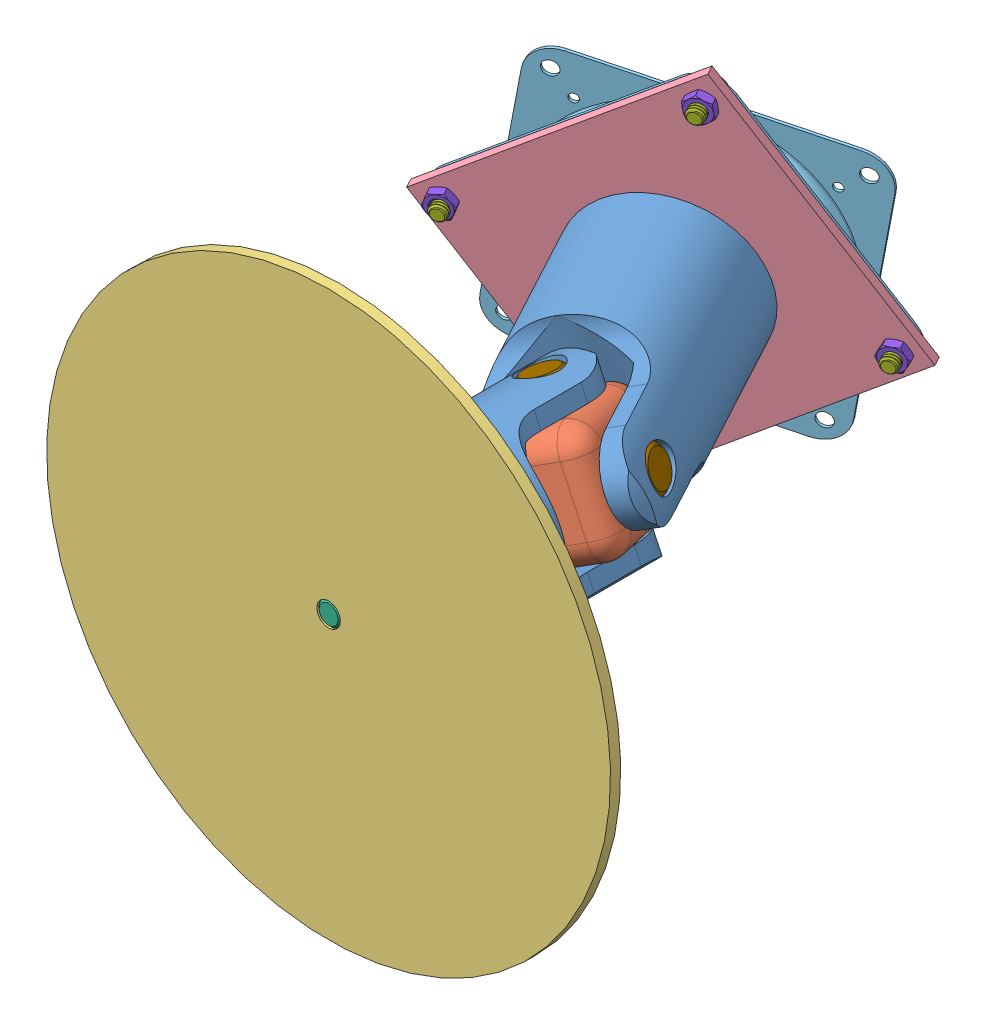
SolidWorks assembly THE_DESIGN, configuration Default. Lengths in mm.
Overall size (177.34 177.34 151.11).
20 component instances, 9 part files, 37 mates.
Components (placement in the parent):
- BandS-4: BandS [2456K19] at (14.9451 4.1501 -66.2661) x (0 0 -1) z (-0.90616 -0.422935 0) size (74.61 44.45 48.36)
- Block-2: Block [Default] at (15.7688 4.5345 -63.9692) x (-0.422935 0.90616 0) z (0.842579 0.39326 -0.367977) size (29.6 29.6 29.6)
- BandS-5: BandS [2456K19] at (16.5925 4.9189 -61.6724) x (0.435787 -0.09635 0.894878) z (-0.316465 0.914365 0.25256) size (74.61 44.45 48.36)
- Base-2: Base [Default] at (14.9451 4.1501 -2.7661) x (-0.983677 0.179942 0) z (0.179942 0.983677 0) size (152.4 38.33 152.4)
- Plate for Turntable-2: Plate for Turntable [Default] at (-12.1869 11.2819 -120.7701) x (-0.482689 0.814165 0.322719) z (0.759672 0.572584 -0.308295) size (76.2 2.54 76.2)
- Square Turntable-1: Square Turntable [6031K16] at (-14.3373 11.7561 -125.0648) x (0.195857 0.980579 0.010199) z (-0.878482 0.170823 0.446194) size (101.18 8.13 101.18)
- Dowel Pin for Top Plate-1: Dowel Pin for Top Plate [90145A815] at (-10.7341 10.9607 -117.7868) x (-0.435787 0.09635 -0.894878) z (-0.298955 -0.9533 0.042945) size (7.94 6.35 6.35)
- Screw for Top Plate-1: Screw for Top Plate [91735A191] at (31.3428 2.7338 -134.8417) x (-0.776957 0.461627 0.428064) z (-0.435787 0.09635 -0.894878) size (8.18 8.18 10.92)
- Screw for Top Plate-2: Screw for Top Plate [91735A191] at (-0.0803 55.7361 -113.8327) x (-0.776957 0.461627 0.428064) z (-0.435787 0.09635 -0.894878) size (8.18 8.18 10.92)
- Screw for Top Plate-3: Screw for Top Plate [91735A191] at (-49.5351 18.4607 -93.7626) x (-0.824863 0.355066 0.43992) z (-0.435787 0.09635 -0.894878) size (8.18 8.18 10.92)
- Screw for Top Plate-4: Screw for Top Plate [91735A191] at (-18.112 -34.5415 -114.7717) x (-0.776957 0.461627 0.428064) z (-0.435787 0.09635 -0.894878) size (8.18 8.18 10.92)
- Hex Nut-1: Hex Nut [90760A009] at (29.8305 3.0681 -137.9472) x (0.776957 -0.461627 -0.428064) z (0.454344 0.881826 -0.126311) size (6.35 2.99 7.33)
- Hex Nut-2: Hex Nut [90760A009] at (-1.5926 56.0704 -116.9381) x (0.377161 0.922297 -0.084367) z (-0.817215 0.374279 0.438264) size (6.35 2.99 7.33)
- Hex Nut-3: Hex Nut [90760A009] at (-19.1857 -34.017 -118.0702) x (0.293981 -0.924484 -0.2427) z (-0.850685 -0.368843 0.374553) size (6.35 2.99 7.33)
- Hex Nut-4: Hex Nut [90760A009] at (-51.5064 18.6956 -96.6553) x (-0.13288 0.976471 0.169845) z (0.890187 0.192928 -0.41273) size (6.35 2.99 7.33)
- Dowel Pin for Top Plate-2: Dowel Pin for Top Plate [90145A815] at (14.9451 4.1501 -3.9688) x (0 0 -1) z (0.392839 -0.919607 0) size (7.94 6.35 6.35)
- Dowel Pin for U-Joint-8: Dowel Pin for U-Joint [98381A665] at (29.4922 10.9397 -67.3061) x (0.842579 0.39326 -0.367977) z (-0.421823 0.906673 0.003094) size (12.7 11.11 11.11)
- Dowel Pin for U-Joint-9: Dowel Pin for U-Joint [98381A665] at (8.4701 18.0232 -66.2661) x (0.422935 -0.90616 0) z (0 0 1) size (12.7 11.11 11.11)
- Dowel Pin for U-Joint-10: Dowel Pin for U-Joint [98381A665] at (21.4202 -9.7231 -66.2661) x (0.422935 -0.90616 0) z (0 0 -1) size (12.7 11.11 11.11)
- Dowel Pin for U-Joint-11: Dowel Pin for U-Joint [98381A665] at (3.6927 -1.1018 -56.0387) x (0.842579 0.39326 -0.367977) z (-0.504894 0.814588 -0.28553) size (12.7 11.11 11.11)
Mates (geometry in assembly coordinates):
- Concentric4: concentric: cylinder of BandS-4 through (5.5454 24.2895 -66.2661) axis (0.422935 -0.90616 0) radius 5.5563; cylinder of Block-2 through (18.7346 -3.969 -66.2661) axis (0.422935 -0.90616 0) radius 5.588
- Coincident23: coincident: plane of BandS-4 through (28.8243 26.9626 -48.0225) normal (0.422935 -0.90616 0); plane of Block-2 through (1.9725 14.43 -44.7592) normal (-0.422935 0.90616 0)
- Concentric7: concentric: cylinder of BandS-5 through (-8.3127 10.4253 -112.8147) axis (-0.435787 0.09635 -0.894878) radius 3.175; cylinder of Plate for Turntable-2 through (-12.1869 11.2819 -120.7701) axis (0.435787 -0.09635 0.894878) radius 3.175
- Concentric8: concentric: cylinder of Plate for Turntable-2 through (28.2047 3.4276 -141.2857) axis (0.435787 -0.09635 0.894878) radius 2.032; cylinder of Square Turntable-1 through (27.8837 3.4986 -141.9448) axis (-0.435787 0.09635 -0.894878) radius 1.9844
- Coincident27: coincident: plane of Plate for Turntable-2 through (-12.1869 11.2819 -120.7701) normal (-0.435787 0.09635 -0.894878); plane of Square Turntable-1 through (-5.4658 45.1777 -120.3936) normal (0.435787 -0.09635 0.894878)
- Parallel15: parallel: plane of Plate for Turntable-2 through (-21.6331 -41.798 -119.0467) normal (-0.759672 -0.572584 0.308295); plane of Square Turntable-1 through (-126.3031 35.25 -233.743) normal (-0.759672 -0.572584 0.308295)
- Concentric14: concentric: cylinder of BandS-5 through (-8.3127 10.4253 -112.8147) axis (-0.435787 0.09635 -0.894878) radius 3.175; cylinder of Dowel Pin for Top Plate-1 through (-9.0046 10.5783 -114.2353) axis (-0.435787 0.09635 -0.894878) radius 3.175
- Coincident34: coincident: circle of Plate for Turntable-2; circle of Dowel Pin for Top Plate-1
- Coincident36: coincident: plane of Square Turntable-1 through (-5.7868 45.2487 -121.0528) normal (-0.435787 0.09635 -0.894878); plane of Screw for Top Plate-1 through (27.8837 3.4986 -141.9448) normal (0.435787 -0.09635 0.894878)
- Concentric16: concentric: cylinder of Square Turntable-1 through (27.8837 3.4986 -141.9448) axis (-0.435787 0.09635 -0.894878) radius 1.9844; cylinder of Screw for Top Plate-1 through (31.3428 2.7338 -134.8417) axis (-0.435787 0.09635 -0.894878) radius 2.0828
- Coincident37: coincident: plane of Square Turntable-1 through (-5.7868 45.2487 -121.0528) normal (-0.435787 0.09635 -0.894878); plane of Screw for Top Plate-2 through (-3.5394 56.5009 -120.9358) normal (0.435787 -0.09635 0.894878)
- Concentric17: concentric: cylinder of Square Turntable-1 through (-3.5394 56.5009 -120.9358) axis (-0.435787 0.09635 -0.894878) radius 1.9844; cylinder of Screw for Top Plate-2 through (-0.0803 55.7361 -113.8327) axis (-0.435787 0.09635 -0.894878) radius 2.0828
- Coincident38: coincident: plane of Square Turntable-1 through (-5.7868 45.2487 -121.0528) normal (-0.435787 0.09635 -0.894878); plane of Screw for Top Plate-3 through (-52.9942 19.2255 -100.8657) normal (0.435787 -0.09635 0.894878)
- Concentric18: concentric: cylinder of Square Turntable-1 through (-52.9942 19.2255 -100.8657) axis (-0.435787 0.09635 -0.894878) radius 1.9844; cylinder of Screw for Top Plate-3 through (-49.5351 18.4607 -93.7626) axis (-0.435787 0.09635 -0.894878) radius 2.0828
- Coincident39: coincident: plane of Square Turntable-1 through (-5.7868 45.2487 -121.0528) normal (-0.435787 0.09635 -0.894878); plane of Screw for Top Plate-4 through (-21.5711 -33.7768 -121.8748) normal (0.435787 -0.09635 0.894878)
- Concentric19: concentric: cylinder of Square Turntable-1 through (-21.5711 -33.7768 -121.8748) axis (-0.435787 0.09635 -0.894878) radius 1.9844; cylinder of Screw for Top Plate-4 through (-18.112 -34.5415 -114.7717) axis (-0.435787 0.09635 -0.894878) radius 2.0828
- Concentric21: concentric: cylinder of Screw for Top Plate-1 through (31.3428 2.7338 -134.8417) axis (-0.435787 0.09635 -0.894878) radius 2.0828; cylinder of Hex Nut-1 through (29.3116 3.1829 -139.0127) axis (0.435787 -0.09635 0.894878) radius 2.0828
- Coincident42: coincident: plane of Plate for Turntable-2 through (-11.08 11.0371 -118.4971) normal (0.435787 -0.09635 0.894878); plane of Hex Nut-2 through (-1.8109 52.5708 -118.5391) normal (-0.435787 0.09635 -0.894878)
- Concentric22: concentric: cylinder of Screw for Top Plate-2 through (-0.0803 55.7361 -113.8327) axis (-0.435787 0.09635 -0.894878) radius 2.0828; cylinder of Hex Nut-2 through (-2.1115 56.1852 -118.0036) axis (0.435787 -0.09635 0.894878) radius 2.0828
- Coincident43: coincident: plane of Plate for Turntable-2 through (-11.08 11.0371 -118.4971) normal (0.435787 -0.09635 0.894878); plane of Hex Nut-3 through (-19.0786 -30.2909 -119.0517) normal (-0.435787 0.09635 -0.894878)
- Tangent13: tangent: cylinder of Screw for Top Plate-4 through (-18.112 -34.5415 -114.7717) axis (-0.435787 0.09635 -0.894878) radius 2.0828; face of Hex Nut-3
- Coincident44: coincident: plane of Plate for Turntable-2 through (-11.08 11.0371 -118.4971) normal (0.435787 -0.09635 0.894878); plane of Hex Nut-4 through (-53.2351 15.3564 -97.5034) normal (-0.435787 0.09635 -0.894878)
- Tangent16: tangent: cylinder of Screw for Top Plate-3 through (-49.5351 18.4607 -93.7626) axis (-0.435787 0.09635 -0.894878) radius 2.0828; face of Hex Nut-4
- Coincident45: coincident: plane of Base-2 through (14.9451 4.1501 0) normal (0 0 1); plane of Dowel Pin for Top Plate-2 through (14.9451 4.1501 0) normal (0 0 1)
- Concentric24: concentric: cylinder of Base-2 through (14.9451 4.1501 0) axis (0 0 -1) radius 3.175; cylinder of Dowel Pin for Top Plate-2 through (14.9451 4.1501 0) axis (0 0 -1) radius 3.175
- Coincident59: coincident: plane of Plate for Turntable-2 through (-11.08 11.0371 -118.4971) normal (0.435787 -0.09635 0.894878); plane of Hex Nut-1 through (26.0119 3.0321 -137.422) normal (-0.435787 0.09635 -0.894878)
- Coincident60: coincident: circle of BandS-5; circle of Plate for Turntable-2
- Concentric26: concentric: circle of Block-2; circle of BandS-5
- Concentric29: concentric: cylinder of Block-2 through (24.1418 8.4425 -64.9694) axis (0.842579 0.39326 -0.367977) radius 5.588; cylinder of Dowel Pin for U-Joint-8 through (24.1418 8.4425 -64.9694) axis (0.842579 0.39326 -0.367977) radius 5.5563
- Coincident66: coincident: plane of Block-2 through (24.1418 8.4425 -64.9694) normal (0.842579 0.39326 -0.367977); circle of Dowel Pin for U-Joint-8
- Coincident69: coincident: plane of Block-2 through (28.2405 10.3555 -69.416) normal (0.842579 0.39326 -0.367977); plane of BandS-5 through (28.1473 -7.8241 -89.058) normal (-0.842579 -0.39326 0.367977)
- Coincident70: coincident: plane of Block-2 through (11.1557 12.2691 -66.2661) normal (-0.422935 0.90616 0); plane of Dowel Pin for U-Joint-9 through (11.1557 12.2691 -66.2661) normal (0.422935 -0.90616 0)
- Concentric33: concentric: cylinder of Block-2 through (11.1557 12.2691 -66.2661) axis (-0.422935 0.90616 0) radius 5.588; cylinder of Dowel Pin for U-Joint-9 through (5.7844 23.7773 -66.2661) axis (0.422935 -0.90616 0) radius 5.5563
- Coincident72: coincident: plane of Block-2 through (18.7346 -3.969 -66.2661) normal (0.422935 -0.90616 0); plane of Dowel Pin for U-Joint-10 through (18.7346 -3.969 -66.2661) normal (-0.422935 0.90616 0)
- Concentric34: concentric: cylinder of Block-2 through (18.7346 -3.969 -66.2661) axis (0.422935 -0.90616 0) radius 5.588; cylinder of Dowel Pin for U-Joint-10 through (18.7346 -3.969 -66.2661) axis (0.422935 -0.90616 0) radius 5.5563
- Concentric35: concentric: cylinder of Block-2 through (9.0431 1.3954 -58.3754) axis (-0.842579 -0.39326 0.367977) radius 5.588; cylinder of Dowel Pin for U-Joint-11 through (-1.6577 -3.599 -53.7021) axis (0.842579 0.39326 -0.367977) radius 5.5563
- Coincident73: coincident: plane of Block-2 through (9.0431 1.3954 -58.3754) normal (-0.842579 -0.39326 0.367977); plane of Dowel Pin for U-Joint-11 through (9.0431 1.3954 -58.3754) normal (0.842579 0.39326 -0.367977)
